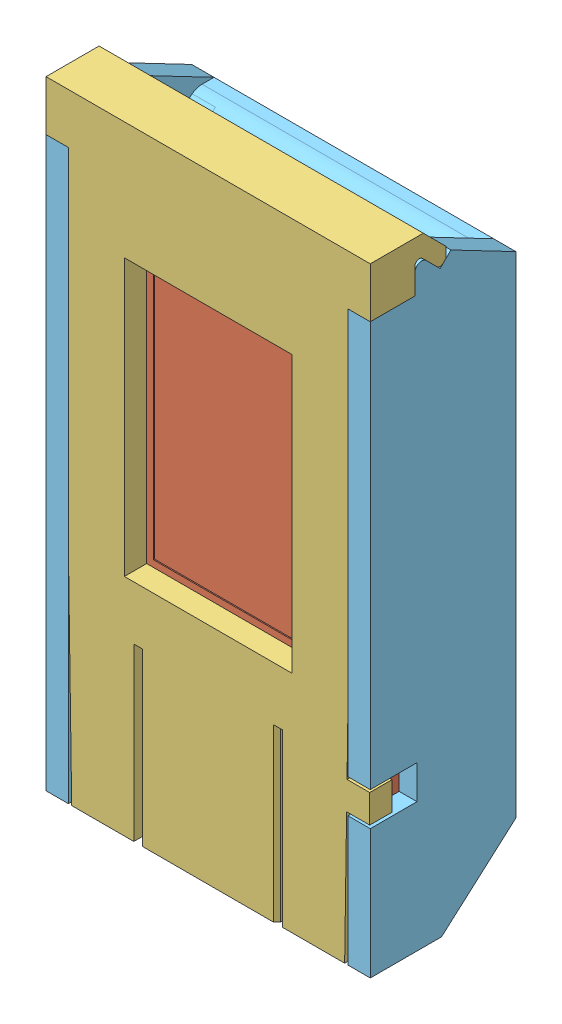
SolidWorks assembly TTGO T-Display, configuration Default. Lengths in mm.
Overall size (29.09 55.52 13.07).
7 component instances, 5 part files, 12 mates.
Components (placement in the parent):
- Assem3-1: Assem3 [Default] at origin size (25.99 53.01 7.4)
  - TTGO T-Display.stp-1: TTGO T-Display.stp [Default] at origin size (25.99 53.01 7.4)
    - USB Type C Port (SMD Type).stp-1: USB Type C Port (SMD Type).stp [Default] at (12.545 5.776 2.875) x (1 0 0) z (0 0 -1) size (8.94 7.9 4.2)
    - TTGO T-Display.stp-1: TTGO T-Display.stp [Default] at origin size (25.99 51.49 7.1)
- Part4-1: Part4 [Default] at (0 0 1.27) size (29.09 55.49 6.81)
- battery-1: battery [Default] x (-1 0 0) z (0 0 -1) size (21 33 4.5)
- back_cover-1: back_cover [Default] at (0 0 -6.5) x (-1 0 0) z (0 0 -1) size (29.09 53.41 13.07)
Mates (geometry in assembly coordinates):
- InPlace1: in place: plane of Assem3-1/TTGO T-Display.stp-1/TTGO T-Display.stp-1 through (0 0 1.27) normal (0 0 1); plane of Part4-1 through (0 0 1.27) normal (0 0 1); moOrthogonalPlaneRef_w of Assem3-1/TTGO T-Display.stp-1/TTGO T-Display.stp-1 through (0 0 1.27) normal (0 0 1); plane of Part4-1 through (0 0 1.27) normal (0 1 0); plane of Assem3-1/TTGO T-Display.stp-1/TTGO T-Display.stp-1 through (0 0 1.27) normal (0 0 1); plane of Part4-1 through (0 0 1.27) normal (1 0 0); plane of Assem3-1/TTGO T-Display.stp-1/TTGO T-Display.stp-1 through (0 0 1.27) normal (0 0 1); unknown of Part4-1
- Coincident1: coincident aligned: plane of ?; plane of ?
- Coincident2: coincident aligned: moOrthogonalPlaneRef_w of Assem3^TTGO T-Display-1/TTGO T-Display.stp-1/TTGO T-Display.stp-1 through (0 0 1.27) normal (0 1 0); plane of Part4-1 through (0 0 1.27) normal (0 1 0)
- Coincident3: coincident anti-aligned: moOrthogonalPlaneRef_w of Assem3^TTGO T-Display-1/TTGO T-Display.stp-1/TTGO T-Display.stp-1 through (0 0 1.27) normal (-1 0 0); plane of Part4-1 through (0 0 1.27) normal (1 0 0)
- InPlace2: in place: plane of Assem3-1/TTGO T-Display.stp-1/TTGO T-Display.stp-1 through (0 0 0) normal (0 0 -1); plane of battery-1 through (0 0 0) normal (0 0 -1); plane of Assem3-1/TTGO T-Display.stp-1/TTGO T-Display.stp-1 through (0 0 0) normal (0 0 -1); plane of battery-1 through (0 0 0) normal (0 1 0); plane of Assem3-1/TTGO T-Display.stp-1/TTGO T-Display.stp-1 through (0 0 0) normal (0 0 -1); plane of battery-1 through (0 0 0) normal (-1 0 0); plane of Assem3-1/TTGO T-Display.stp-1/TTGO T-Display.stp-1 through (0 0 0) normal (0 0 -1); unknown of battery-1
- Coincident4: coincident aligned: plane of ?; plane of ?
- Coincident5: coincident aligned: moOrthogonalPlaneRef_w of Assem3-1/TTGO T-Display.stp-1/TTGO T-Display.stp-1 through (0 0 0) normal (0 1 0); plane of Part5^TTGO T-Display-1 through (0 0 0) normal (0 1 0)
- Coincident6: coincident anti-aligned: moOrthogonalPlaneRef_w of Assem3-1/TTGO T-Display.stp-1/TTGO T-Display.stp-1 through (0 0 0) normal (1 0 0); plane of Part5^TTGO T-Display-1 through (0 0 0) normal (-1 0 0)
- InPlace3: in place: plane of battery-1 through (0 0 -6.5) normal (0 0 -1); plane of back_cover-1 through (0 0 -6.5) normal (0 0 -1); plane of battery-1 through (0 0 -6.5) normal (0 0 -1); plane of back_cover-1 through (0 0 -6.5) normal (0 1 0); plane of battery-1 through (0 0 -6.5) normal (0 0 -1); plane of back_cover-1 through (0 0 -6.5) normal (-1 0 0); plane of battery-1 through (0 0 -6.5) normal (0 0 -1); unknown of back_cover-1
- Coincident7: coincident aligned: plane of ?; plane of ?
- Coincident8: coincident aligned: moOrthogonalPlaneRef_w of battery^TTGO T-Display-1 through (0 0 -6.5) normal (0 1 0); plane of back_cover-1 through (0 0 -6.5) normal (0 1 0)
- Coincident9: coincident anti-aligned: moOrthogonalPlaneRef_w of battery^TTGO T-Display-1 through (0 0 -6.5) normal (1 0 0); plane of back_cover-1 through (0 0 -6.5) normal (-1 0 0)
